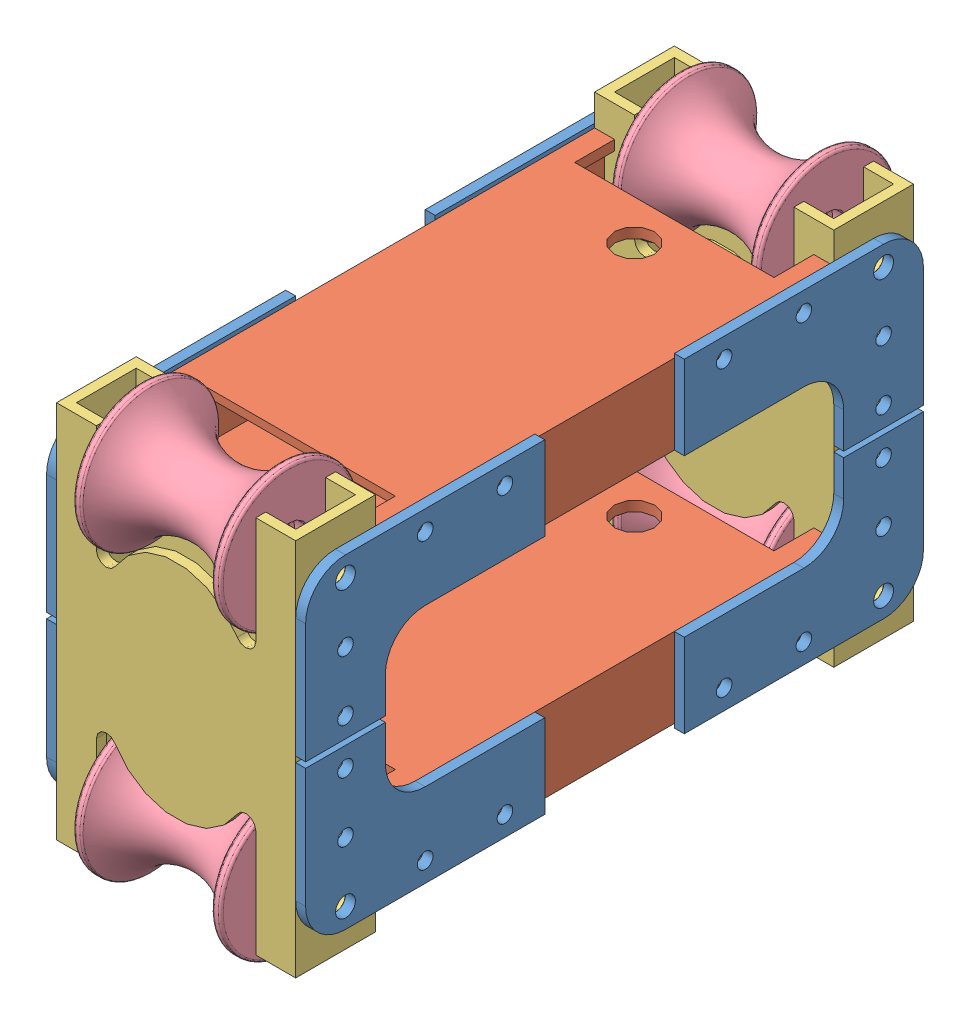
SolidWorks assembly 240-000 Carage, configuration Default. Lengths in mm.
Overall size (82.55 148.07 228.84).
16 component instances, 4 part files, 40 mates.
Components (placement in the parent):
- 240-003 Carage Braket-1: 240-003 Carage Braket [Default] at (-41.275 13.97 -98.425) x (0 -1 0) z (1 0 0) size (50.8 76.2 3.17)
- 240-003 Carage Braket-2: 240-003 Carage Braket [Default] at (38.1 -89.408 98.425) x (0 1 0) z (1 0 0) size (50.8 76.2 3.17)
- 240-003 Carage Braket-3: 240-003 Carage Braket [Default] at (41.275 13.97 98.425) x (0 -1 0) z (-1 0 0) size (50.8 76.2 3.17)
- 240-003 Carage Braket-4: 240-003 Carage Braket [Default] at (38.1 13.97 -98.425) x (0 -1 0) z (1 0 0) size (50.8 76.2 3.17)
- 240-003 Carage Braket-5: 240-003 Carage Braket [Default] at (41.275 -89.408 -98.425) x (0 1 0) z (-1 0 0) size (50.8 76.2 3.17)
- 240-003 Carage Braket-6: 240-003 Carage Braket [Default] at (-41.275 -89.408 98.425) x (0 1 0) z (1 0 0) size (50.8 76.2 3.17)
- 240-003 Carage Braket-7: 240-003 Carage Braket [Default] at (-38.1 13.97 98.425) x (0 -1 0) z (-1 0 0) size (50.8 76.2 3.17)
- 240-003 Carage Braket-8: 240-003 Carage Braket [Default] at (-38.1 -89.408 -98.425) x (0 1 0) z (-1 0 0) size (50.8 76.2 3.17)
- 240-002 leg-1: 240-002 leg [Default] at (0 -75.438 0) x (-1 0 0) z (0 0 1) size (76.2 25.4 146.05)
- 240-002 leg-2: 240-002 leg [Default] at origin size (76.2 25.4 146.05)
- 240-001 base-1: 240-001 base [Default] at (0 -110.744 85.725) x (1 0 0) z (0 1 0) size (76.2 25.4 120.65)
- 240-001 base-2: 240-001 base [Default] at (0 -110.744 -85.725) x (1 0 0) z (0 1 0) size (76.2 25.4 120.65)
- 200-001 Roller 3-1: 200-001 Roller 3 [Default] at (0 7.62 -85.725) x (0 -0.381849 0.924225) z (0 -0.924225 -0.381849) size (43.94 46.98 43.94)
- 200-001 Roller 3-2: 200-001 Roller 3 [Default] at (0 -83.058 -85.725) x (0 -0.160081 -0.987104) z (0 0.987104 -0.160081) size (43.94 46.98 43.94)
- 200-001 Roller 3-3: 200-001 Roller 3 [Default] at (0 -83.058 85.725) x (0 0.381849 -0.924225) z (0 -0.924225 -0.381849) size (43.94 46.98 43.94)
- 200-001 Roller 3-4: 200-001 Roller 3 [Default] at (0 7.62 85.725) x (0 -0.381849 0.924225) z (0 -0.924225 -0.381849) size (43.94 46.98 43.94)
Mates (geometry in assembly coordinates):
- Concentric1: concentric: cylinder of 240-003 Carage Braket-4 through (41.275 7.62 -60.325) axis (-1 0 0) radius 2.4892; cylinder of 240-002 leg-2 through (-38.1 7.62 -60.325) axis (1 0 0) radius 2.4892
- Concentric2: concentric: cylinder of 240-003 Carage Braket-5 through (38.1 -83.058 -85.725) axis (1 0 0) radius 3.175; cylinder of 240-001 base-2 through (-38.1 -83.058 -85.725) axis (1 0 0) radius 3.175
- Concentric3: concentric: cylinder of 240-003 Carage Braket-5 through (38.1 -83.058 -60.325) axis (1 0 0) radius 2.4892; cylinder of 240-002 leg-1 through (38.1 -83.058 -60.325) axis (-1 0 0) radius 2.4892
- Concentric4: concentric: cylinder of 240-003 Carage Braket-4 through (41.275 7.62 -85.725) axis (-1 0 0) radius 3.175; cylinder of 240-001 base-2 through (-38.1 7.62 -85.725) axis (1 0 0) radius 3.175
- Concentric5: concentric: cylinder of 240-003 Carage Braket-7 through (-41.275 7.62 60.325) axis (1 0 0) radius 2.4892; cylinder of 240-002 leg-2 through (-38.1 7.62 60.325) axis (1 0 0) radius 2.4892
- Concentric6: concentric: cylinder of 240-003 Carage Braket-6 through (-38.1 -83.058 85.725) axis (-1 0 0) radius 3.175; cylinder of 240-001 base-1 through (-38.1 -83.058 85.725) axis (1 0 0) radius 3.175
- Concentric7: concentric: cylinder of 240-003 Carage Braket-2 through (41.275 -64.008 85.725) axis (-1 0 0) radius 2.4892; cylinder of 240-001 base-1 through (38.1 -64.008 85.725) axis (-1 0 0) radius 2.4892
- Concentric8: concentric: cylinder of 240-003 Carage Braket-6 through (-38.1 -83.058 60.325) axis (-1 0 0) radius 2.4892; cylinder of 240-002 leg-1 through (38.1 -83.058 60.325) axis (-1 0 0) radius 2.4892
- Concentric9: concentric: cylinder of 240-003 Carage Braket-7 through (-41.275 7.62 85.725) axis (1 0 0) radius 3.175; cylinder of 240-001 base-1 through (-38.1 7.62 85.725) axis (1 0 0) radius 3.175
- Coincident1: coincident: plane of 240-002 leg-2 through (0 0 73.025) normal (0 0 1); plane of 240-001 base-1 through (-38.1 35.306 73.025) normal (0 0 -1)
- Coincident2: coincident: plane of 240-002 leg-2 through (-38.1 -12.7 73.025) normal (-1 0 0); plane of 240-001 base-1 through (-38.1 35.306 98.425) normal (-1 0 0)
- Coincident3: coincident: circle of 240-003 Carage Braket-3; cylinder of 240-002 leg-2 through (-38.1 7.62 60.325) axis (1 0 0) radius 2.4892
- Coincident4: coincident: cylinder of 240-003 Carage Braket-8 through (-41.275 -83.058 -85.725) axis (1 0 0) radius 3.175; circle of 240-001 base-2
- Coincident5: coincident: plane of 240-003 Carage Braket-5 through (38.1 -89.408 -98.425) normal (-1 0 0); plane of 240-001 base-2 through (38.1 35.306 -73.025) normal (1 0 0)
- Coincident6: coincident: plane of 240-003 Carage Braket-7 through (-38.1 13.97 98.425) normal (1 0 0); plane of 240-001 base-1 through (-38.1 35.306 98.425) normal (-1 0 0)
- Coincident7: coincident: plane of 240-003 Carage Braket-6 through (-38.1 -89.408 98.425) normal (1 0 0); plane of 240-001 base-1 through (-38.1 35.306 98.425) normal (-1 0 0)
- Coincident8: coincident: cylinder of 240-003 Carage Braket-2 through (41.275 -83.058 85.725) axis (-1 0 0) radius 3.175; circle of 240-001 base-1
- Coincident9: coincident: circle of 240-003 Carage Braket-3; circle of 240-001 base-1
- Coincident10: coincident: plane of 240-003 Carage Braket-8 through (-38.1 -89.408 -98.425) normal (1 0 0); plane of 240-002 leg-1 through (-38.1 -62.738 73.025) normal (-1 0 0)
- Coincident11: coincident: plane of 240-003 Carage Braket-2 through (38.1 -89.408 98.425) normal (-1 0 0); plane of 240-001 base-1 through (38.1 35.306 98.425) normal (1 0 0)
- Coincident12: coincident: plane of 240-003 Carage Braket-4 through (38.1 13.97 -98.425) normal (-1 0 0); plane of 240-001 base-2 through (38.1 35.306 -73.025) normal (1 0 0)
- Coincident13: coincident: plane of 240-002 leg-1 through (38.1 -62.738 73.025) normal (1 0 0); plane of 240-001 base-1 through (38.1 35.306 98.425) normal (1 0 0)
- Coincident14: coincident: plane of 240-002 leg-1 through (0 -75.438 73.025) normal (0 0 1); plane of 240-001 base-1 through (-38.1 35.306 73.025) normal (0 0 -1)
- Coincident15: coincident: plane of 240-003 Carage Braket-1 through (-38.1 13.97 -98.425) normal (1 0 0); plane of 240-002 leg-2 through (-38.1 -12.7 73.025) normal (-1 0 0)
- Coincident16: coincident: plane of 240-002 leg-2 through (0 0 -73.025) normal (0 0 -1); plane of 240-001 base-2 through (-38.1 35.306 -73.025) normal (0 0 1)
- Parallel1: parallel: plane of 240-003 Carage Braket-2 through (41.275 -89.408 98.425) normal (1 0 0); plane of 240-003 Carage Braket-3 through (41.275 13.97 98.425) normal (1 0 0)
- Width4: width: plane of 240-001 base-2 through (-113.2116 276.2285 64.7905) normal (1 0 0); plane of 240-001 base-2 through (-67.4916 276.2285 64.7905) normal (-1 0 0); plane of ? through (-108.0046 384.3047 60.5823) normal (-1 0 0); plane of ? through (-72.6986 384.3047 60.5823) normal (1 0 0)
- Concentric13: concentric: cylinder of 240-003 Carage Braket-1 through (-38.1 7.62 -85.725) axis (-1 0 0) radius 3.175; cylinder of 240-001 base-2 through (-38.1 7.62 -85.725) axis (1 0 0) radius 3.175
- Concentric14: concentric: cylinder of 240-003 Carage Braket-8 through (-41.275 -83.058 -60.325) axis (1 0 0) radius 2.4892; cylinder of 240-002 leg-1 through (38.1 -83.058 -60.325) axis (-1 0 0) radius 2.4892
- Concentric16: concentric: cylinder of 240-003 Carage Braket-1 through (-38.1 7.62 -60.325) axis (-1 0 0) radius 2.4892; cylinder of 240-002 leg-2 through (-38.1 7.62 -60.325) axis (1 0 0) radius 2.4892
- Coincident17: coincident: plane of 240-003 Carage Braket-4 through (38.1 13.97 -98.425) normal (-1 0 0); plane of 240-002 leg-2 through (38.1 -12.7 73.025) normal (1 0 0)
- Coincident18: coordinate: point of 240-002 leg-2; point of assembly
- Width5: width: plane of 200-001 Roller 3-2 through (23.4903 -83.058 -85.725) normal (1 0 0); plane of 200-001 Roller 3-2 through (-23.4903 -83.058 -85.725) normal (-1 0 0); plane of 240-001 base-2 through (34.925 35.306 -85.725) normal (-1 0 0); plane of 240-001 base-2 through (-34.925 35.306 -85.725) normal (1 0 0)
- Concentric17: concentric: cylinder of 240-003 Carage Braket-5 through (38.1 -83.058 -85.725) axis (1 0 0) radius 3.175; cylinder of 200-001 Roller 3-2 through (-23.4903 -83.058 -85.725) axis (-1 0 0) radius 6.35
- Concentric18: concentric: cylinder of 240-003 Carage Braket-1 through (-38.1 7.62 -85.725) axis (-1 0 0) radius 3.175; cylinder of 200-001 Roller 3-1 through (-23.4903 7.62 -85.725) axis (-1 0 0) radius 6.35
- Coincident19: coincident: plane of 200-001 Roller 3-1 through (-23.4903 7.62 -85.725) normal (-1 0 0); plane of 200-001 Roller 3-2 through (-23.4903 -83.058 -85.725) normal (-1 0 0)
- Coincident20: coincident: plane of 200-001 Roller 3-2 through (-23.4903 -83.058 -85.725) normal (-1 0 0); plane of 200-001 Roller 3-4 through (-23.4903 7.62 85.725) normal (-1 0 0)
- Concentric19: concentric: cylinder of 240-001 base-1 through (-38.1 7.62 85.725) axis (1 0 0) radius 3.175; cylinder of 200-001 Roller 3-4 through (-23.4903 7.62 85.725) axis (-1 0 0) radius 6.35
- Concentric20: concentric: cylinder of 240-001 base-1 through (-38.1 -83.058 85.725) axis (1 0 0) radius 3.175; cylinder of 200-001 Roller 3-3 through (23.4903 -83.058 85.725) axis (1 0 0) radius 6.35
- Coincident21: coincident: plane of 200-001 Roller 3-2 through (-23.4903 -83.058 -85.725) normal (-1 0 0); plane of 200-001 Roller 3-3 through (-23.4903 -83.058 85.725) normal (-1 0 0)
